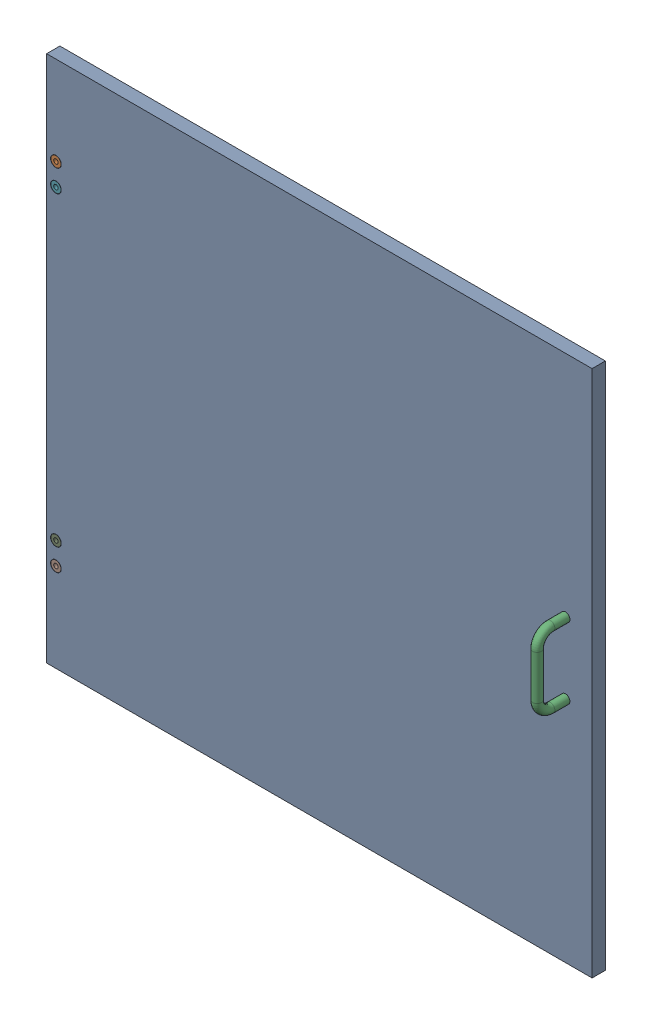
SolidWorks assembly s-assy-frontlarge, configuration ﾃﾞﾌｫﾙﾄ. Lengths in mm.
Overall size (615 595 53).
12 component instances, 5 part files, 12 mates.
Components (placement in the parent):
- plate_front_large-1: plate_front_large [ﾃﾞﾌｫﾙﾄ] at origin size (615 595 15)
- Onimenut_m5-1: Onimenut_m5 [ﾃﾞﾌｫﾙﾄ] at (-297 197.5 2) x (0 0 -1) z (1 0 0) size (13 11.5 11.5)
- MISUMI_C-NUWANS10-80-27-1: MISUMI_C-NUWANS10-80-27 [Default] at (277.5 0 15) x (0 -1 0) z (-1 0 0) size (90 37 10)
- Onimenut_m3-1: Onimenut_m3 [ﾃﾞﾌｫﾙﾄ] at (298 197.5 0) x (1 0.000579 0) z (0 0 1) size (4 4 8.5)
- MISUMI_E-GCBSTSR5-20-1: MISUMI_E-GCBSTSR5-20 [Default] at (277.5 40 0) x (0 0 1) z (-0.309344 0.95095 0) size (21 9 9)
- MISUMI_E-GCBSTSR5-20-2: MISUMI_E-GCBSTSR5-20 [Default] at (277.5 -40 0) x (0 0 1) z (-0.309344 0.95095 0) size (21 9 9)
- Onimenut_m5-3: Onimenut_m5 [ﾃﾞﾌｫﾙﾄ] at (-297 172.5 2) x (0 0 -1) z (1 0 0) size (13 11.5 11.5)
- Onimenut_m5-4: Onimenut_m5 [ﾃﾞﾌｫﾙﾄ] at (-297 -197.5 2) x (0 0 -1) z (-1 0 0) size (13 11.5 11.5)
- Onimenut_m5-5: Onimenut_m5 [ﾃﾞﾌｫﾙﾄ] at (-297 -172.5 2) x (0 0 -1) z (-1 0 0) size (13 11.5 11.5)
- Onimenut_m3-2: Onimenut_m3 [ﾃﾞﾌｫﾙﾄ] at (298 167.5 0) x (1 0.000579 0) z (0 0 1) size (4 4 8.5)
- Onimenut_m3-3: Onimenut_m3 [ﾃﾞﾌｫﾙﾄ] at (298 -197.5 8.5) x (1 -0.000579 0) z (0 0 -1) size (4 4 8.5)
- Onimenut_m3-4: Onimenut_m3 [ﾃﾞﾌｫﾙﾄ] at (298 -167.5 8.5) x (1 -0.000579 0) z (0 0 -1) size (4 4 8.5)
Mates (geometry in assembly coordinates):
- 一致1: coordinate: point of plate_front_large-1
- 同心円1: concentric anti-aligned: cylinder of plate_front_large-1 through (-297 197.5 0) axis (0 0 1) radius 4; cylinder of Onimenut_m5-1 through (-297 197.5 2) axis (0 0 -1) radius 5.5
- 一致2: coincident anti-aligned: plane of plate_front_large-1 through (-297 197.5 14) normal (0 0 1); plane of Onimenut_m5-1 through (-297 197.5 14) normal (0 0 -1)
- 同心円2: concentric anti-aligned: cylinder of plate_front_large-1 through (277.5 40 0) axis (0 0 1) radius 2.5; cylinder of MISUMI_C-NUWANS10-80-27-1 through (277.5 40 32) axis (0 0 -1) radius 5
- 同心円3: concentric anti-aligned: cylinder of plate_front_large-1 through (277.5 -40 0) axis (0 0 1) radius 2.5; cylinder of MISUMI_C-NUWANS10-80-27-1 through (277.5 -40 32) axis (0 0 -1) radius 5
- 一致3: coincident anti-aligned: plane of plate_front_large-1 through (0 0 15) normal (0 0 1); plane of MISUMI_C-NUWANS10-80-27-1 through (277.5 40 15) normal (0 0 -1)
- 一致4: coincident anti-aligned: plane of plate_front_large-1 through (0 0 0) normal (0 0 -1); circle of Onimenut_m3-1
- 同心円5: concentric anti-aligned: cylinder of plate_front_large-1 through (277.5 40 0) axis (0 0 1) radius 2.5; cylinder of MISUMI_E-GCBSTSR5-20-1 through (277.5 40 -1) axis (0 0 -1) radius 2.5
- 一致5: coincident anti-aligned: plane of plate_front_large-1 through (0 0 0) normal (0 0 -1); plane of MISUMI_E-GCBSTSR5-20-1 through (279.6444 40.6976 0) normal (0 0 1)
- 同心円6: concentric anti-aligned: cylinder of plate_front_large-1 through (277.5 -40 0) axis (0 0 1) radius 2.5; cylinder of MISUMI_E-GCBSTSR5-20-2 through (277.5 -40 -1) axis (0 0 -1) radius 2.5
- 一致6: coincident anti-aligned: plane of plate_front_large-1 through (0 0 0) normal (0 0 -1); plane of MISUMI_E-GCBSTSR5-20-2 through (279.6444 -39.3024 0) normal (0 0 1)
- 同心円7: concentric aligned: cylinder of plate_front_large-1 through (298 197.5 9) axis (0 0 -1) radius 2; cylinder of Onimenut_m3-1 through (298 197.5 8.5) axis (0 0 -1) radius 2
